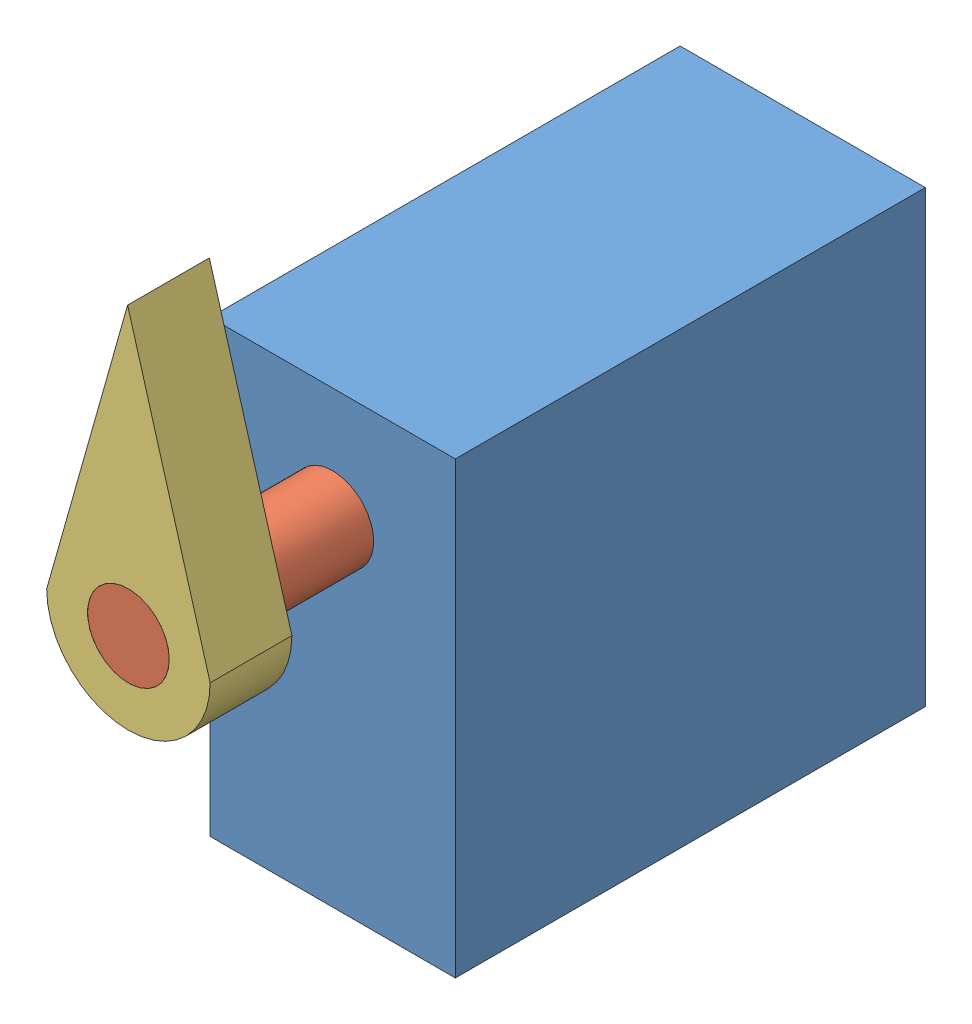
SolidWorks assembly servo_assembly, configuration Default. Lengths in mm.
Overall size (12 30.51 33).
3 component instances, 3 part files, 4 mates.
Components (placement in the parent):
- servo_motor-1: servo_motor [Default] at (24.5095 7.7148 17.7383) x (0 1 0) z (0 0 1) size (22 12 23)
- servo_shaft-1: servo_shaft [Default] at (18.5095 24.2148 29.7383) x (0.76883 -0.639453 0) z (0 0 1) size (4 4 21)
- servo_motor_plug-1: servo_motor_plug [Default] at (18.5095 24.2148 46.7383) x (-0.999996 -0.002736 0) z (0 0 1) size (8 18 4)
Mates (geometry in assembly coordinates):
- Coincident1: coincident: plane of servo_motor-1 through (18.5095 24.2148 29.7383) normal (0 0 1); plane of servo_shaft-1 through (18.5095 24.2148 29.7383) normal (0 0 -1)
- Concentric1: concentric anti-aligned: cylinder of servo_motor-1 through (18.5095 24.2148 29.7383) axis (0 0 1) radius 2; cylinder of servo_shaft-1 through (18.5095 24.2148 50.7383) axis (0 0 -1) radius 2
- Concentric2: concentric aligned: cylinder of servo_shaft-1 through (18.5095 24.2148 50.7383) axis (0 0 -1) radius 2; cylinder of servo_motor_plug-1 through (18.5095 24.2148 50.7383) axis (0 0 -1) radius 2
- Coincident2: coincident aligned: plane of servo_shaft-1 through (18.5095 24.2148 50.7383) normal (0 0 1); plane of servo_motor_plug-1 through (18.5095 24.2148 50.7383) normal (0 0 1)
